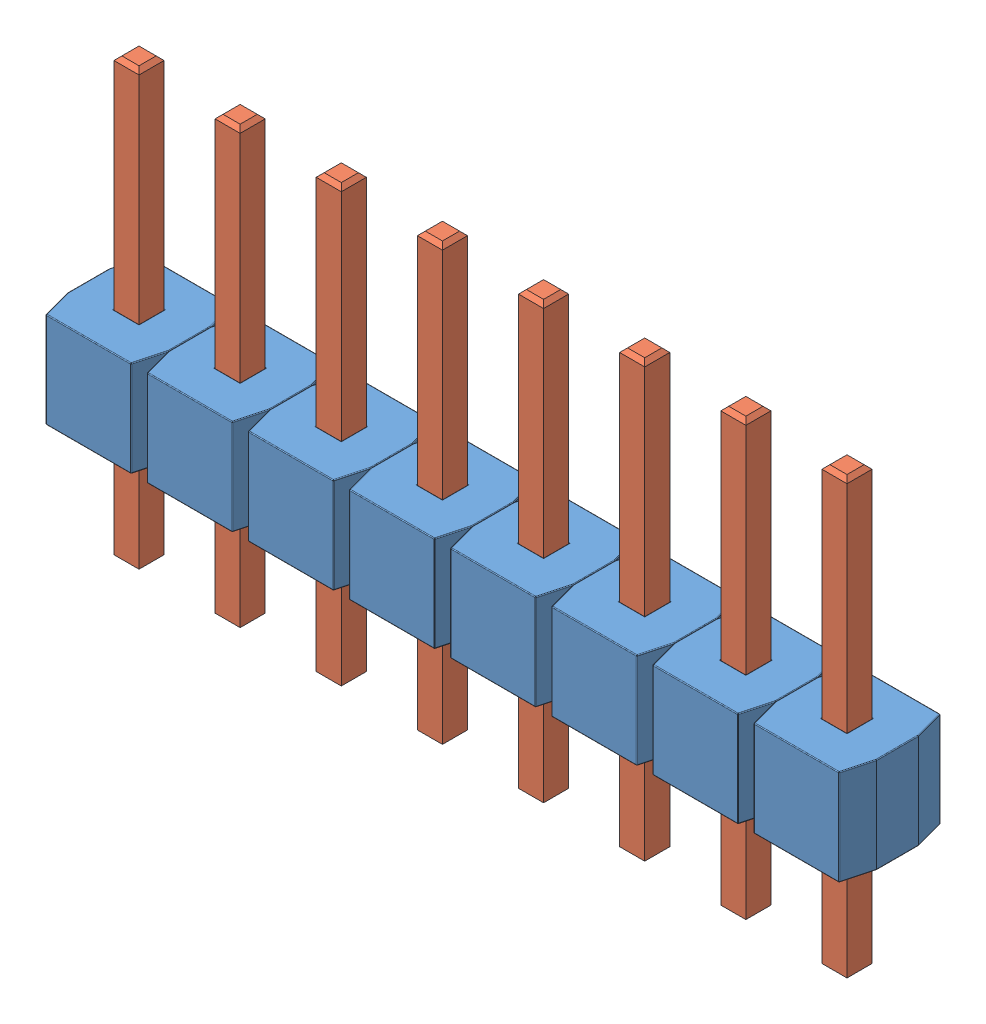
SolidWorks assembly Male Header Pin Config, configuration 11 pin. Lengths in mm.
Overall size (20.32 10.95 2.54).
16 component instances, 2 part files, 1 mates.
Components (placement in the parent):
- Spacer-1: Spacer [Default] at origin
- Male Header Pin-1: Male Header Pin [Default] at (0 -3.03 0) x (0 0 1) z (-1 0 0)
- Spacer-2: Spacer [Default] at (2.54 0 0)
- Male Header Pin-2: Male Header Pin [Default] at (2.54 -3.03 0) x (0 0 1) z (-1 0 0)
- Spacer-3: Spacer [Default] at (5.08 0 0)
- Spacer-4: Spacer [Default] at (7.62 0 0)
- Spacer-5: Spacer [Default] at (10.16 0 0)
- Spacer-6: Spacer [Default] at (12.7 0 0)
- Spacer-7: Spacer [Default] at (15.24 0 0)
- Spacer-8: Spacer [Default] at (17.78 0 0)
- Male Header Pin-3: Male Header Pin [Default] at (5.08 -3.03 0) x (0 0 1) z (-1 0 0)
- Male Header Pin-4: Male Header Pin [Default] at (7.62 -3.03 0) x (0 0 1) z (-1 0 0)
- Male Header Pin-5: Male Header Pin [Default] at (10.16 -3.03 0) x (0 0 1) z (-1 0 0)
- Male Header Pin-6: Male Header Pin [Default] at (12.7 -3.03 0) x (0 0 1) z (-1 0 0)
- Male Header Pin-7: Male Header Pin [Default] at (15.24 -3.03 0) x (0 0 1) z (-1 0 0)
- Male Header Pin-8: Male Header Pin [Default] at (17.78 -3.03 0) x (0 0 1) z (-1 0 0)
Mates (geometry in assembly coordinates):
- ProfileCenter1: profile center = 5.52 mm aligned: plane of Male Header Pin-1 through (0 7.92 0) normal (0 1 0); plane of Spacer-1 through (0 2.4 0) normal (0 1 0)
